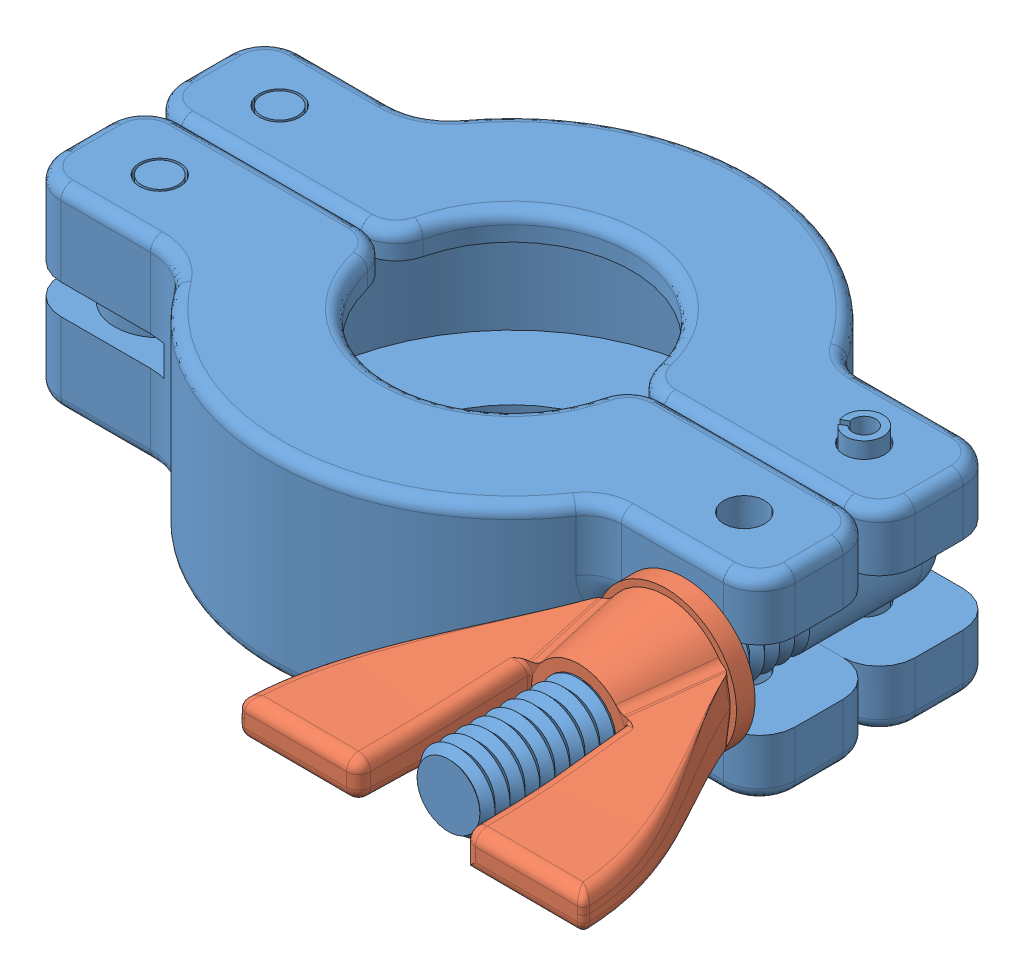
SolidWorks assembly 701000, configuration Default. Lengths in mm.
Overall size (70.93 17.78 53.83).
2 component instances, 2 part files, 2 mates.
Components (placement in the parent):
- sub2-1: sub2 [Default] at (3.3536 31.2066 43.2684) size (62.23 17.78 50.6)
- sub1-1: sub1 [Default] at (3.468 34.6136 37.187) x (0.997749 -0.067066 0) z (0 0 1) size (29.36 11.99 23.23)
Mates (geometry in assembly coordinates):
- Concentric1: concentric aligned: circle of sub2-1; cylinder of sub1-1 through (54.1536 31.2066 52.5003) axis (0 0 -1) radius 3.3147
- Coincident1: coincident anti-aligned: plane of sub2-1 through (60.5036 39.4616 50.9255) normal (0 0 1); plane of sub1-1 through (53.6099 31.2432 50.9255) normal (0 0 -1)
